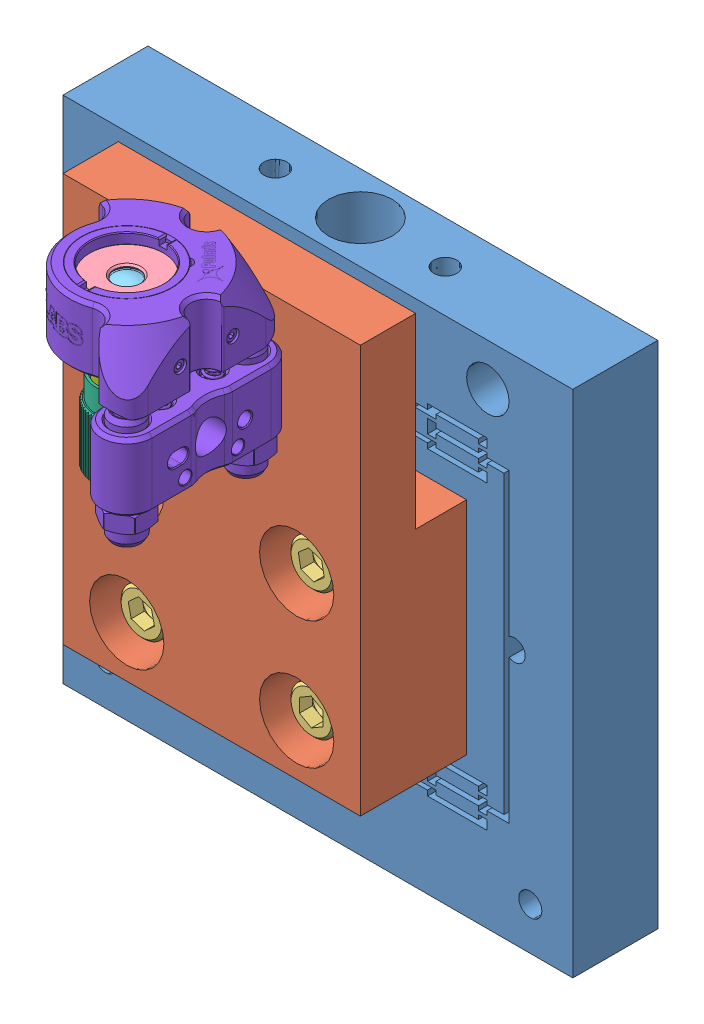
SolidWorks assembly Readhead, configuration Default. Lengths in mm.
Overall size (76.2 88.05 53.97).
11 component instances, 8 part files, 23 mates.
Components (placement in the parent):
- Actuator2-2: Actuator2 [Default] at (-27.5516 86.6533 32.1917) size (76.2 76.2 12.7)
- StageMount1-2: StageMount1 [Default] at (-27.5516 99.9883 46.4792) size (44.45 60.96 15.88)
- socket head cap screw_ai-1: socket head cap screw_ai [HX-SHCS 0.164-32x0.5x0.5-N] at (-14.8516 96.1783 52.2323) x (0 0 -1) z (0.982252 0.187567 0) size (16.87 6.86 6.86)
- socket head cap screw_ai-2: socket head cap screw_ai [HX-SHCS 0.164-32x0.5x0.5-N] at (-14.8516 77.1283 52.2323) x (0 0 -1) z (0.491828 0.870692 0) size (16.87 6.86 6.86)
- socket head cap screw_ai-3: socket head cap screw_ai [HX-SHCS 0.164-32x0.5x0.5-N] at (-40.2516 77.1283 52.2323) x (0 0 -1) z (0.976439 0.215795 0) size (16.87 6.86 6.86)
- socket head cap screw_ai-4: socket head cap screw_ai [HX-SHCS 0.164-32x0.5x0.5-N] at (-40.2516 96.1783 52.2323) x (0 0 -1) z (0.993643 0.11258 0) size (16.87 6.86 6.86)
- LMRA5-Solidworks-1: LMRA5-Solidworks [Default] at (-27.5516 134.8046 67.1167) x (-0.546944 0 0.837169) z (0 -1 0) size (12.69 12.69 2.16)
- 355390-C-Solidworks-1: 355390-C-Solidworks [Default] at (-27.5516 133.605 67.1167) x (0 1 0) z (-0.546944 0 0.837169) size (1.9 4.5 4.5)
- 30126C9-Solidworks-1: 30126C9-Solidworks [Default] at (-27.5516 118.1481 67.1167) x (0 0 -1) z (0 1 0) size (9.99 9.99 22.73)
- SM05FC-Solidworks-1: SM05FC-Solidworks [Default] at (-27.5516 126.1491 67.1167) x (-1 0 0) z (0 -1 0) size (13.59 13.59 8.28)
- POLARIS-K05T6-Solidworks-1: POLARIS-K05T6-Solidworks [Default] at (-25.7736 131.6296 65.3387) x (0 0 -1) z (0 1 0) size (25.4 25.4 26.73)
Mates (geometry in assembly coordinates):
- Concentric3: concentric aligned: circle of Actuator2-2; circle of StageMount1-2
- Concentric4: concentric aligned: circle of Actuator2-2; circle of StageMount1-2
- Coincident2: coincident anti-aligned: plane of Actuator2-2 through (-27.5516 86.6533 38.5417) normal (0 0 1); plane of StageMount1-2 through (-27.5516 99.9883 38.5417) normal (0 0 -1)
- Concentric5: concentric aligned: circle of StageMount1-2; circle of socket head cap screw_ai-2
- Coincident3: coincident anti-aligned: plane of StageMount1-2 through (-11.4734 77.1283 48.0667) normal (0 0 1); plane of socket head cap screw_ai-2 through (-17.8372 78.8148 48.0667) normal (0 0 -1)
- Concentric6: concentric aligned: circle of StageMount1-2; circle of socket head cap screw_ai-1
- Coincident4: coincident anti-aligned: plane of StageMount1-2 through (-11.4734 96.1783 48.0667) normal (0 0 1); plane of socket head cap screw_ai-1 through (-15.4948 99.5464 48.0667) normal (0 0 -1)
- Concentric7: concentric aligned: circle of StageMount1-2; circle of socket head cap screw_ai-4
- Concentric8: concentric aligned: circle of StageMount1-2; circle of socket head cap screw_ai-3
- Coincident5: coincident anti-aligned: plane of StageMount1-2 through (-36.8734 77.1283 48.0667) normal (0 0 1); plane of socket head cap screw_ai-3 through (-40.9916 80.4765 48.0667) normal (0 0 -1)
- Coincident6: coincident anti-aligned: plane of StageMount1-2 through (-36.8734 96.1783 48.0667) normal (0 0 1); plane of socket head cap screw_ai-4 through (-40.6376 99.5855 48.0667) normal (0 0 -1)
- Concentric9: concentric anti-aligned: circle of LMRA5-Solidworks-1; circle of 355390-C-Solidworks-1
- Coincident7: coincident anti-aligned: plane of LMRA5-Solidworks-1 through (-26.2864 134.1696 67.9433) normal (0 -1 0); plane of 355390-C-Solidworks-1 through (-27.5516 134.1696 67.1167) normal (0 1 0)
- Concentric10: concentric aligned: circle of LMRA5-Solidworks-1; circle of POLARIS-K05T6-Solidworks-1
- Coincident8: coincident anti-aligned: plane of LMRA5-Solidworks-1 through (-27.5516 134.8046 67.1167) normal (0 1 0); plane of POLARIS-K05T6-Solidworks-1 through (-33.1396 134.8046 67.1167) normal (0 -1 0)
- Concentric11: concentric anti-aligned: circle of SM05FC-Solidworks-1; circle of POLARIS-K05T6-Solidworks-1
- Distance1: distance = 2.75 mm anti-aligned: plane of SM05FC-Solidworks-1 through (-27.5516 129.8956 62.3542) normal (0 1 0); plane of LMRA5-Solidworks-1 through (-27.5516 132.6456 67.1167) normal (0 -1 0)
- Concentric12: concentric anti-aligned: circle of 30126C9-Solidworks-1; circle of SM05FC-Solidworks-1
- Parallel2: parallel anti-aligned: plane of 30126C9-Solidworks-1 through (-30.3578 129.5146 66.1007) normal (0 0 -1); plane of SM05FC-Solidworks-1 through (-23.4562 119.3853 66.0372) normal (0 0 1)
- Coincident14: coincident anti-aligned: circle of 30126C9-Solidworks-1; plane of SM05FC-Solidworks-1 through (-27.5516 125.4506 67.1167) normal (0 -1 0)
- Concentric13: concentric anti-aligned: circle of StageMount1-2; circle of POLARIS-K05T6-Solidworks-1
- Coincident15: coincident anti-aligned: plane of StageMount1-2 through (-27.5516 99.9883 54.4167) normal (0 0 1); plane of POLARIS-K05T6-Solidworks-1 through (-18.6616 114.8473 54.4167) normal (0 0 -1)
- Parallel3: parallel aligned: plane of StageMount1-2 through (-49.7766 130.4683 54.4167) normal (0 1 0); plane of POLARIS-K05T6-Solidworks-1 through (7.5452 136.4556 61.8572) normal (0 1 0)
